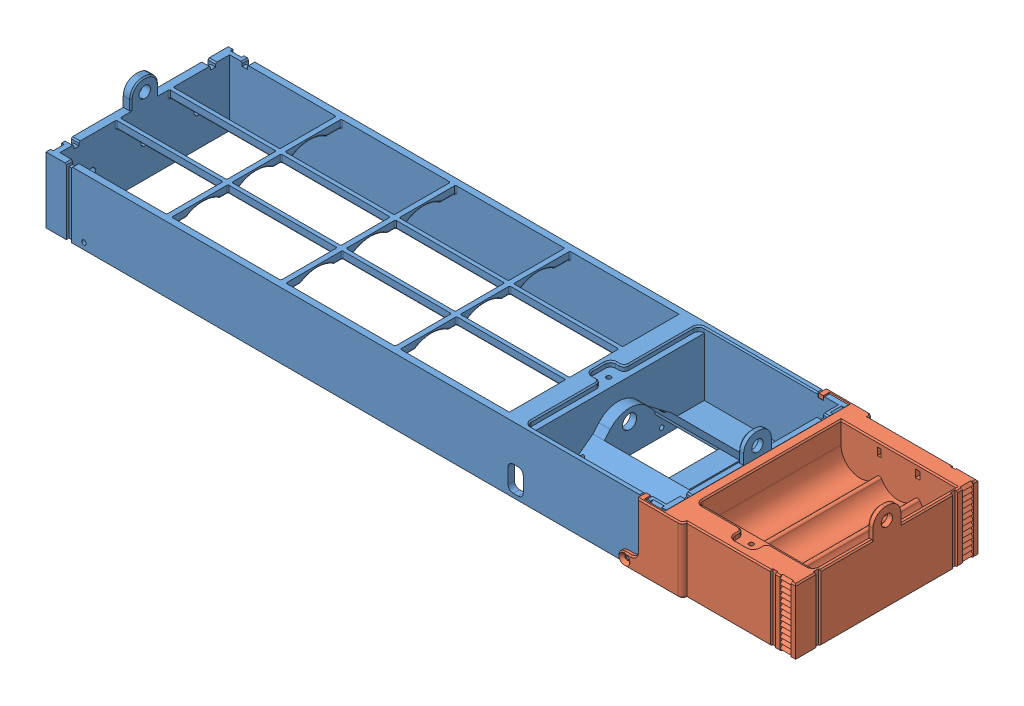
SolidWorks assembly Assem_Option_3x2, configuration Default. Lengths in mm.
Overall size (296.1 35 75.55).
2 component instances, 2 part files, 3 mates.
Components (placement in the parent):
- Main_Frame-1: Main_Frame [Default] at (-2.8302 -23.261 5.4074) size (245 35 72)
- Option_3x2_Battery-1: Option_3x2_Battery [Default] at (145.2698 -23.261 5.4074) x (-1 0 0) z (0 0 -1) size (68.7 35 75.55)
Mates (geometry in assembly coordinates):
- Width1: width anti-aligned: plane of Option_3x2_Battery-1 through (119.7698 -41.4338 41.5074) normal (0 0 -1); plane of Option_3x2_Battery-1 through (119.7698 -41.4338 -30.6926) normal (0 0 1); plane of Main_Frame-1 through (119.6698 2.739 41.4074) normal (0 0 1); plane of Main_Frame-1 through (119.6698 2.739 -30.5926) normal (0 0 -1)
- Coincident1: coincident anti-aligned: plane of Main_Frame-1 through (-2.8302 1.239 5.4074) normal (0 1 0); plane of Option_3x2_Battery-1 through (145.2698 1.239 5.4074) normal (0 -1 0)
- Concentric1: concentric aligned: circle of Main_Frame-1; circle of Option_3x2_Battery-1
